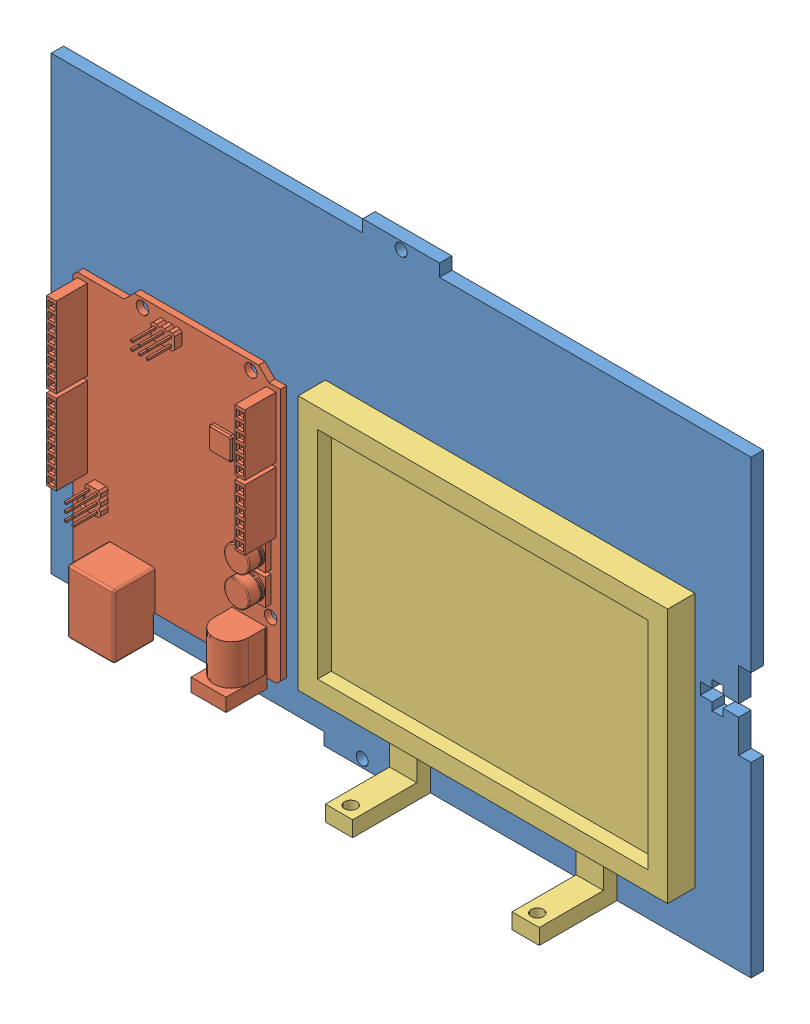
SolidWorks assembly PIDfloor, configuration Default. Lengths in mm.
Overall size (180 122.36 23.18).
3 component instances, 3 part files, 13 mates.
Components (placement in the parent):
- PIDbox.floor-1: PIDbox.floor [Default] at (48.4438 98.4116 143.425) size (180 122.36 3.18)
- ArduinoUno-1: ArduinoUno [Default] at (-7.6525 79.6116 146.605) x (0 1 0) z (1 0 0) size (74.8 12.1 53.3)
- PIDbox.breadboardholder-1: PIDbox.breadboardholder [Default] at (76.4718 86.0516 146.605) size (95 78.44 20)
Mates (geometry in assembly coordinates):
- Coincident1: coincident anti-aligned: plane of PIDbox.floor-1 through (48.4438 98.4116 146.605) normal (0 0 1); plane of ArduinoUno-1 through (-34.3025 112.6116 146.605) normal (0 0 -1)
- Parallel2: parallel: line of PIDbox.floor-1 through (28.5688 40.4116 146.605) axis (-1 0 0); plane of ArduinoUno-1 through (-25.3025 40.4116 158.705) normal (0 -1 0)
- Coincident4: coincident anti-aligned: plane of PIDbox.floor-1 through (48.4438 98.4116 146.605) normal (0 0 1); plane of ArduinoUno-1 through (-34.3025 112.6116 146.605) normal (0 0 -1)
- Parallel3: parallel aligned: plane of PIDbox.floor-1 through (-41.5562 159.5916 146.605) normal (-1 0 0); plane of ArduinoUno-1 through (-34.3025 111.6116 148.205) normal (-1 0 0)
- Coincident6: coincident aligned: plane of PIDbox.floor-1 through (-41.5562 40.4116 143.425) normal (0 -1 0); plane of ArduinoUno-1 through (-25.3025 40.4116 158.705) normal (0 -1 0)
- Parallel5: parallel: line of PIDbox.floor-1 through (-38.3762 156.4116 146.605) axis (0 -1 0); plane of ArduinoUno-1 through (-34.3025 111.6116 148.205) normal (-1 0 0)
- Coincident7: coincident: plane of ArduinoUno-1 through (-34.3025 111.6116 148.205) normal (-1 0 0)
- Parallel6: parallel aligned: plane of PIDbox.floor-1 through (138.4438 40.4116 143.425) normal (0 -1 0); plane of Half Breadboard-Simple-1 through (28.364 59.2517 154.755) normal (0 -1 0)
- Parallel7: parallel aligned: plane of PIDbox.floor-1 through (138.4438 159.5916 146.605) normal (1 0 0); plane of Half Breadboard-Simple-1 through (112.364 59.2517 154.755) normal (1 0 0)
- Coincident10: coincident anti-aligned: plane of PIDbox.floor-1 through (48.4438 98.4116 146.605) normal (0 0 1); plane of Half Breadboard-Simple-1 through (112.364 113.8517 146.605) normal (0 0 -1)
- Parallel8: parallel anti-aligned: plane of ArduinoUno-1 through (18.9975 112.6116 148.205) normal (1 0 0); plane of Half Breadboard-Simple-1 through (28.364 59.2517 154.755) normal (-1 0 0)
- Coincident12: coincident anti-aligned: plane of PIDbox.floor-1 through (48.4438 98.4116 146.605) normal (0 0 1); plane of PIDbox.breadboardholder-1 through (76.4718 86.0516 146.605) normal (0 0 -1)
- Coincident13: coincident aligned: plane of PIDbox.floor-1 through (138.4438 40.4116 143.425) normal (0 -1 0); plane of PIDbox.breadboardholder-1 through (76.4718 40.4116 166.605) normal (0 -1 0)
